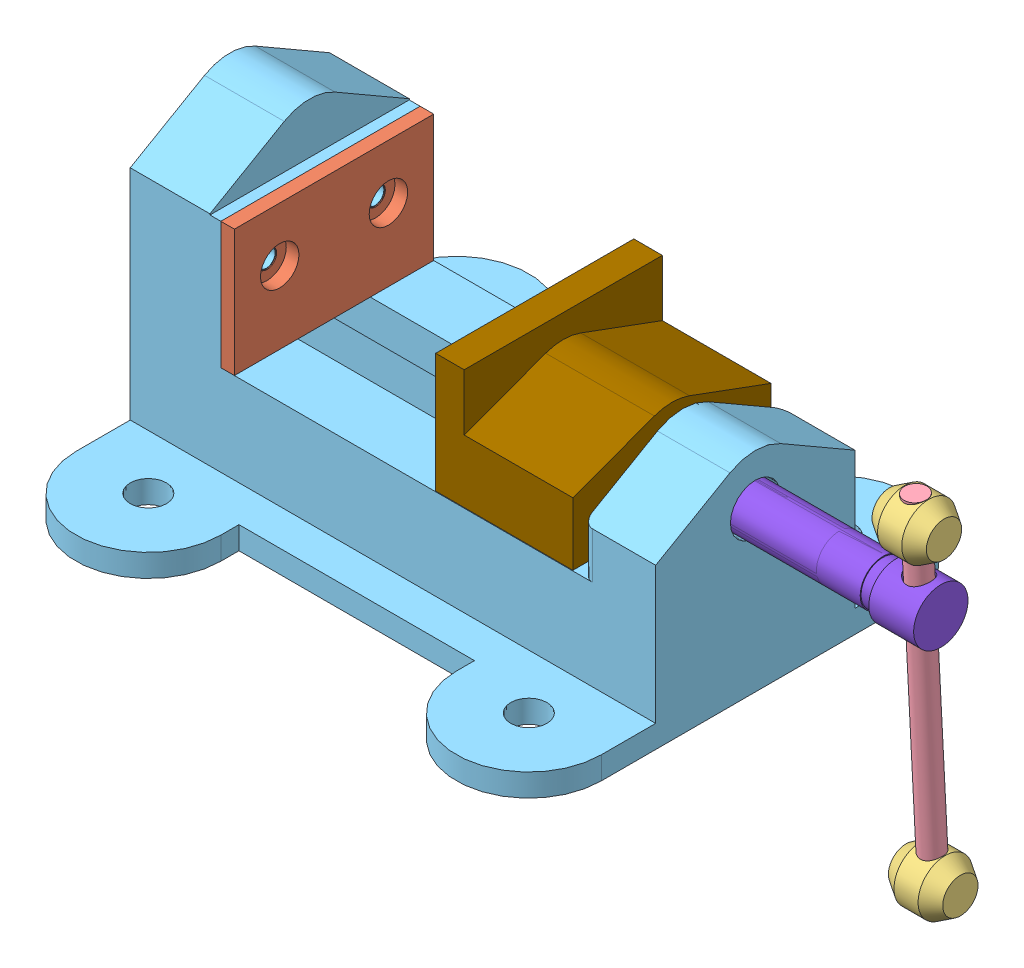
SolidWorks assembly HW8_P1_WONG, configuration Default. Lengths in mm.
Overall size (251.58 142.21 158.75).
11 component instances, 9 part files, 27 mates.
Components (placement in the parent):
- Collar-1: Collar [Default] at (127.2399 55.5625 0) x (0 0.953258 -0.302156) z (-1 0 0) size (18.26 18.26 20.64)
- FlatJawPlate-1: FlatJawPlate [Default] at (31.75 0 0) x (0 0 -1) z (1 0 0) size (69.85 44.45 4.76)
- handle_ball-1: handle_ball [Default] at (242.0516 -30.2925 -4.4387) x (0.00001 -0.051632 0.998666) z (0 0.998666 0.051632) size (19.05 19.05 19.05)
- handle_rod-1: handle_rod [Default] at (242.0516 25.1959 -1.57) x (-0.982092 -0.009727 0.188149) z (0 -0.998666 -0.051632) size (7.94 7.94 130.18)
- BASE-2: BASE [Default] at origin size (184.15 101.92 158.75)
- Lock_Screw-1: Lock_Screw [Default] at (110.8786 55.5625 0) x (0 0.984016 -0.178078) z (1 0 0) size (16.79 18.26 3.17)
- Slide_Key-1: Slide_Key [Default] at (154.9377 27.0011 -6.9882) x (-1 0 0) z (0 -1 0) size (58.74 8.64 4.7)
- vice_screw-1: vice_screw [Default] at (249.1599 55.5625 0) x (-1 0 0) z (0 0.966607 -0.256265) size (142.32 19.05 19.05)
- Slide_Key-2: Slide_Key [Default] at (96.2002 26.9503 6.9882) x (1 0 0) z (0 -1 0) size (58.74 8.64 4.7)
- SlidingJaw-2: SlidingJaw [Default] at (154.9377 1.6011 0) x (0 0 -1) z (1 0 0) size (69.45 79.91 61.91)
- handle_ball-2: handle_ball [Default] at (242.0516 80.6843 1.2988) x (0.000001 -0.051632 0.998666) z (0 -0.998666 -0.051632) size (19.05 19.05 19.05)
Mates (geometry in assembly coordinates):
- Coincident2: coincident aligned: line of FlatJawPlate-1 through (31.75 84.1375 -34.925) axis (0 0 1); line of BASE-2 through (31.75 84.1375 -34.925) axis (0 0 1)
- Concentric4: concentric aligned: circle of FlatJawPlate-1; circle of BASE-2
- Concentric5: concentric aligned: circle of BASE-2; circle of SlidingJaw-2
- Concentric8: concentric aligned: cylinder of handle_rod-1 through (242.0516 -39.8048 -4.9305) axis (0 0.998666 0.051632) radius 3.9688; cylinder of vice_screw-1 through (242.0516 65.0748 0.4918) axis (0 0.998666 0.051632) radius 4.3663
- Concentric23: concentric anti-aligned: cylinder of handle_ball-1 through (242.0516 -20.7802 -3.947) axis (0 -0.998666 -0.051632) radius 3.9688; cylinder of handle_rod-1 through (242.0516 -39.8048 -4.9305) axis (0 0.998666 0.051632) radius 3.9688
- Tangent16: tangent aligned: cylinder of handle_ball-1 through (262.8811 -30.2925 -4.439) axis (1 0.000001 -0.00001) radius 9.525; plane of handle_rod-1 through (242.0516 -39.8048 -4.9305) normal (0 -0.998666 -0.051632)
- Concentric24: concentric aligned: cylinder of handle_rod-1 through (242.0516 -39.8048 -4.9305) axis (0 0.998666 0.051632) radius 3.9688; cylinder of handle_ball-2 through (242.0516 71.172 0.807) axis (0 0.998666 0.051632) radius 3.9688
- Tangent17: tangent aligned: plane of handle_rod-1 through (242.0516 90.1966 1.7906) normal (0 0.998666 0.051632); cylinder of handle_ball-2 through (221.2222 80.6843 1.2988) axis (-1 0 0.000001) radius 9.525
- Concentric25: concentric aligned: cylinder of BASE-2 through (184.15 55.5625 0) axis (1 0 0) radius 8.7312; cylinder of vice_screw-1 through (127.2399 55.5625 0) axis (1 0 0) radius 7.9375
- Coincident14: coincident aligned: plane of Slide_Key-1 through (154.9377 22.3021 -6.9882) normal (1 0 0); plane of SlidingJaw-2 through (154.9377 51.1077 -34.725) normal (1 0 0)
- Coincident15: coincident anti-aligned: plane of Slide_Key-1 through (154.9377 22.3021 -6.9882) normal (0 0 1); plane of SlidingJaw-2 through (116.8377 22.2513 -6.9882) normal (0 0 -1)
- Coincident16: coincident anti-aligned: plane of Slide_Key-1 through (154.9377 27.0011 -15.6242) normal (0 1 0); plane of SlidingJaw-2 through (116.8377 27.0011 -6.9882) normal (0 -1 0)
- Coincident18: coincident anti-aligned: plane of Slide_Key-2 through (96.2002 22.2513 15.6242) normal (0 -1 0); plane of SlidingJaw-2 through (116.8377 22.2513 12.5) normal (0 1 0)
- Coincident19: coincident aligned: plane of Slide_Key-2 through (154.9377 22.2513 6.9882) normal (1 0 0); plane of SlidingJaw-2 through (154.9377 51.1077 -34.725) normal (1 0 0)
- Coincident20: coincident anti-aligned: plane of Slide_Key-2 through (96.2002 22.2513 15.6242) normal (0 -1 0); plane of SlidingJaw-2 through (116.8377 22.2513 12.5) normal (0 1 0)
- Coincident21: coincident anti-aligned: plane of Slide_Key-2 through (96.2002 22.2513 6.9882) normal (0 0 -1); plane of SlidingJaw-2 through (116.8377 22.2513 6.9882) normal (0 0 1)
- Parallel8: parallel anti-aligned: plane of BASE-2 through (0 26.9875 12.7) normal (0 0 -1); plane of SlidingJaw-2 through (116.8377 27.0011 12.5) normal (0 0 1)
- Concentric26: concentric anti-aligned: cylinder of Collar-1 through (106.6024 55.5625 0) axis (1 0 0) radius 6.5484; cylinder of vice_screw-1 through (106.8377 55.5625 0) axis (-1 0 0) radius 6.35
- Coincident23: coincident anti-aligned: plane of Collar-1 through (127.2399 55.5625 0) normal (1 0 0); plane of vice_screw-1 through (127.2399 55.5625 0) normal (-1 0 0)
- Concentric27: concentric aligned: cylinder of Lock_Screw-1 through (114.0536 55.5625 0) axis (-1 0 0) radius 4.9609; cylinder of vice_screw-1 through (106.8377 55.5625 0) axis (-1 0 0) radius 4.7336
- Coincident24: coincident anti-aligned: plane of Lock_Screw-1 through (110.8786 55.5625 0) normal (-1 0 0); plane of vice_screw-1 through (110.8786 56.7756 4.5756) normal (1 0 0)
- Coincident25: coincident aligned: plane of vice_screw-1 through (106.8377 57.1898 6.138) normal (-1 0 0); plane of SlidingJaw-2 through (106.8377 81.5151 -34.725) normal (-1 0 0)
- LimitDistance1: limit distance = 66.9197 mm: cylinder of handle_ball-1 through (262.8811 -30.2925 -4.439) axis (1 0.000001 -0.00001) radius 9.525; cylinder of vice_screw-1 through (90.4099 55.5625 0) axis (1 0 0) radius 9.525
- LimitDistance2: limit distance = 6.1053 mm: cylinder of handle_ball-2 through (221.2222 80.6843 1.2988) axis (-1 0 0.000001) radius 9.525; cylinder of vice_screw-1 through (90.4099 55.5625 0) axis (1 0 0) radius 9.525
- Screw2: screw = 12 aligned: axis of BASE-2 through (25.4 158.75 55.5625) axis (0 1 0); cylinder of vice_screw-1 through (127.2399 55.5625 0) axis (1 0 0) radius 7.9375
- LimitDistance3: limit distance = 3.8123 mm anti-aligned: plane of BASE-2 through (158.75 55.5625 0) normal (-1 0 0); plane of SlidingJaw-2 through (154.9377 51.1077 -34.725) normal (1 0 0)
- LimitDistance4: limit distance = 49.3038 mm anti-aligned: plane of vice_screw-1 through (233.4538 53.6098 -7.3655) normal (-1 0 0); plane of BASE-2 through (184.15 0 34.925) normal (1 0 0)
